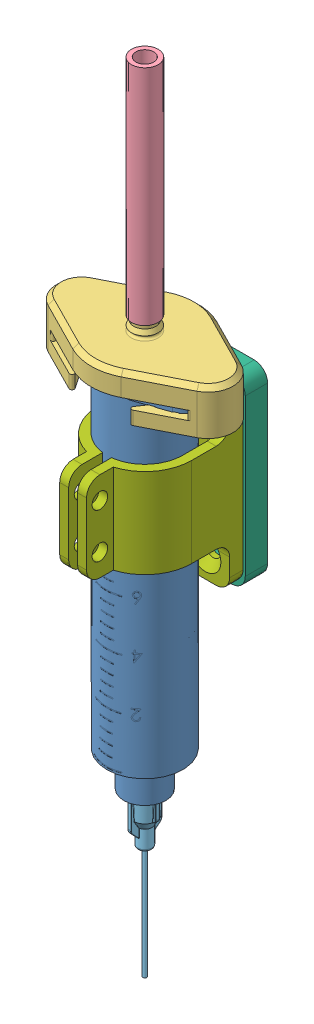
SolidWorks assembly extruder-assembly, configuration Default. Lengths in mm.
Overall size (39.5 178.31 32.56).
9 component instances, 8 part files, 12 mates.
Components (placement in the parent):
- cr10-bracket-2: cr10-bracket [Default] at (11.7311 45.1852 62.0886) x (1 0 0) z (0 -1 0) size (64 22.9 64) (hidden)
- syringe-nozzle-1: syringe-nozzle [Default] at (4.8311 70.1852 81.0886) x (0 -1 0) z (0 0 1) size (144.5 39.5 24)
  - syringe-cylinder-10ml-1: syringe-cylinder-10ml [Default] at origin size (86.5 31 20)
  - rubber-10ml-1: rubber-10ml [Default] at (5.75 0 0) x (-1 0 0) z (0 0.519313 0.854584) size (8.54 15 15)
  - syringe-adapter-10ml-v2-1: syringe-adapter-10ml-v2 [Default] at (-5 0 0) x (0 0 -1) z (0 1 0) size (24 16 39.5)
  - straight-tube-6mm-1: straight-tube-6mm [Default] at (-8 0 0) x (0 1 0) z (0 0 1) size (6 50 6)
- syringe-needle-luer-1: syringe-needle-luer [Yellow_20Gauge] at (4.8311 -24.7276 81.0886) x (0 1 0) z (-0.995284 0 -0.097003) size (43.15 7.7 8.15)
- syringe-mount-1: syringe-mount [Default] at (4.8311 45.1852 64.5886) size (28.1 41 5)
- syringe-holder-10ml-1: syringe-holder-10ml [Default] at (4.8311 45.1852 69.5886) size (21 40 27.56)
Mates (geometry in assembly coordinates):
- Concentric1: concentric aligned: cylinder of syringe-nozzle-1/syringe-cylinder-10ml-1 through (4.8311 -33.3363 81.0886) axis (0 -1 0) radius 4.7; cylinder of syringe-needle-luer-1 through (4.8311 -19.2276 81.0886) axis (0 -1 0) radius 0.455
- Coincident1: coincident anti-aligned: circle of syringe-nozzle-1/syringe-cylinder-10ml-1; plane of syringe-needle-luer-1 through (5.0299 -6.9776 79.0483) normal (0 1 0)
- Concentric3: concentric aligned: cylinder of cr10-bracket-2 through (-7.2689 35.6852 64.5886) axis (0 0 -1) radius 1.75; cylinder of syringe-mount-1 through (-7.2689 35.6852 69.5886) axis (0 0 -1) radius 1.75
- Coincident2: coincident anti-aligned: plane of syringe-mount-1 through (4.8311 45.1852 69.5886) normal (0 0 1); plane of syringe-holder-10ml-1 through (4.8311 45.1852 69.5886) normal (0 0 -1)
- Concentric4: concentric aligned: cylinder of syringe-mount-1 through (9.8311 60.1852 69.5886) axis (0 0 -1) radius 1.75; cylinder of syringe-holder-10ml-1 through (9.8311 60.1852 72.5886) axis (0 0 -1) radius 1.75
- Concentric5: concentric anti-aligned: cylinder of syringe-nozzle-1/syringe-cylinder-10ml-1 through (4.8311 -33.3363 81.0886) axis (0 -1 0) radius 8.5; cylinder of syringe-holder-10ml-1 through (4.8311 35.1852 81.0886) axis (0 1 0) radius 8.5
- Coincident3: coincident anti-aligned: plane of cr10-bracket-2 through (11.7311 45.1852 64.5886) normal (0 0 1); plane of syringe-mount-1 through (4.8311 45.1852 64.5886) normal (0 0 -1)
- Parallel1: parallel aligned: plane of syringe-nozzle-1 through (4.8311 70.1852 81.0886) normal (0 0 1); plane of syringe-holder-10ml-1 through (4.8311 45.1852 69.5886) normal (0 0 1)
- Concentric6: concentric aligned: cylinder of syringe-mount-1 through (9.8311 30.1852 69.5886) axis (0 0 -1) radius 1.75; cylinder of syringe-holder-10ml-1 through (9.8311 30.1852 72.5886) axis (0 0 -1) radius 1.75
- Coincident5: coincident anti-aligned: plane of pump-v2-small-1/nema17-1/Base-1 through (-72.3014 0 45.5684) normal (0 -1 0)
- Parallel2: parallel aligned: plane of pump-v2-small-1/nema17-1/Body-1 through (-93.4514 40.4 66.7184) normal (0 0 1)
- Coincident6: coincident anti-aligned: plane of syringe-nozzle-1/syringe-adapter-10ml-v2-1 through (24.5811 65.1852 81.0886) normal (0 -1 0); plane of syringe-mount-1 through (-5.1689 65.1852 69.5886) normal (0 1 0)
